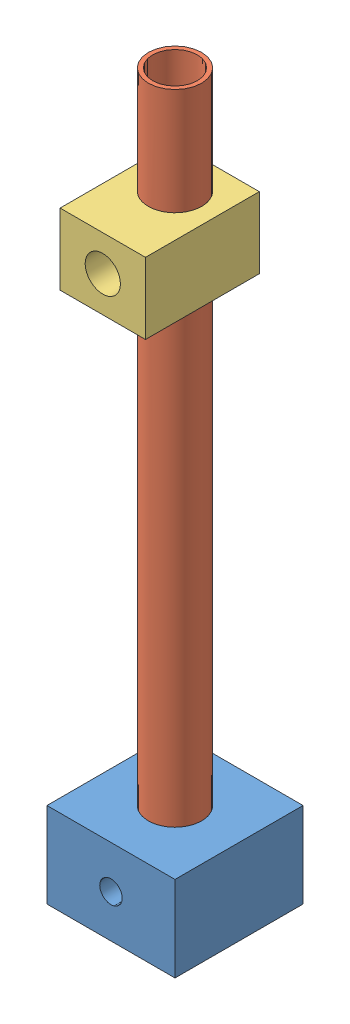
SolidWorks assembly inertia model, configuration Default. Lengths in mm.
Overall size (90 509 95.75).
3 component instances, 3 part files, 5 mates.
Components (placement in the parent):
- first-1: first [Default] at (15.1813 31.7874 89.1119) size (90 60 90)
- cylinder(1)-1: cylinder(1) [Default] at (60.1813 90.7874 89.1119) size (37.5 450 37.5)
- mod1-1: mod1 [Default] at (30.1813 440.7874 139.8619) size (60 50 80)
Mates (geometry in assembly coordinates):
- Concentric1: concentric anti-aligned: cylinder of first-1 through (60.1813 90.7874 89.1119) axis (0 1 0) radius 18.75; cylinder of cylinder(1)-1 through (60.1813 90.7874 89.1119) axis (0 -1 0) radius 18.75
- Coincident2: coincident anti-aligned: plane of first-1 through (60.1813 90.7874 89.1119) normal (0 1 0); plane of cylinder(1)-1 through (44.4313 90.7874 89.1119) normal (0 -1 0)
- Parallel1: parallel aligned: cylinder of first-1 through (60.1813 61.7874 44.1119) axis (0 0 1) radius 7.9; cylinder of cylinder(1)-1 through (60.1813 440.7874 70.3619) axis (0 0 1) radius 12.4
- Concentric3: concentric aligned: cylinder of cylinder(1)-1 through (60.1813 90.7874 89.1119) axis (0 -1 0) radius 18.75; cylinder of mod1-1 through (60.1813 465.7874 89.1119) axis (0 -1 0) radius 18.75
- Concentric4: concentric anti-aligned: cylinder of cylinder(1)-1 through (60.1813 440.7874 70.3619) axis (0 0 1) radius 12.4; cylinder of mod1-1 through (60.1813 440.7874 139.8619) axis (0 0 -1) radius 12.4
